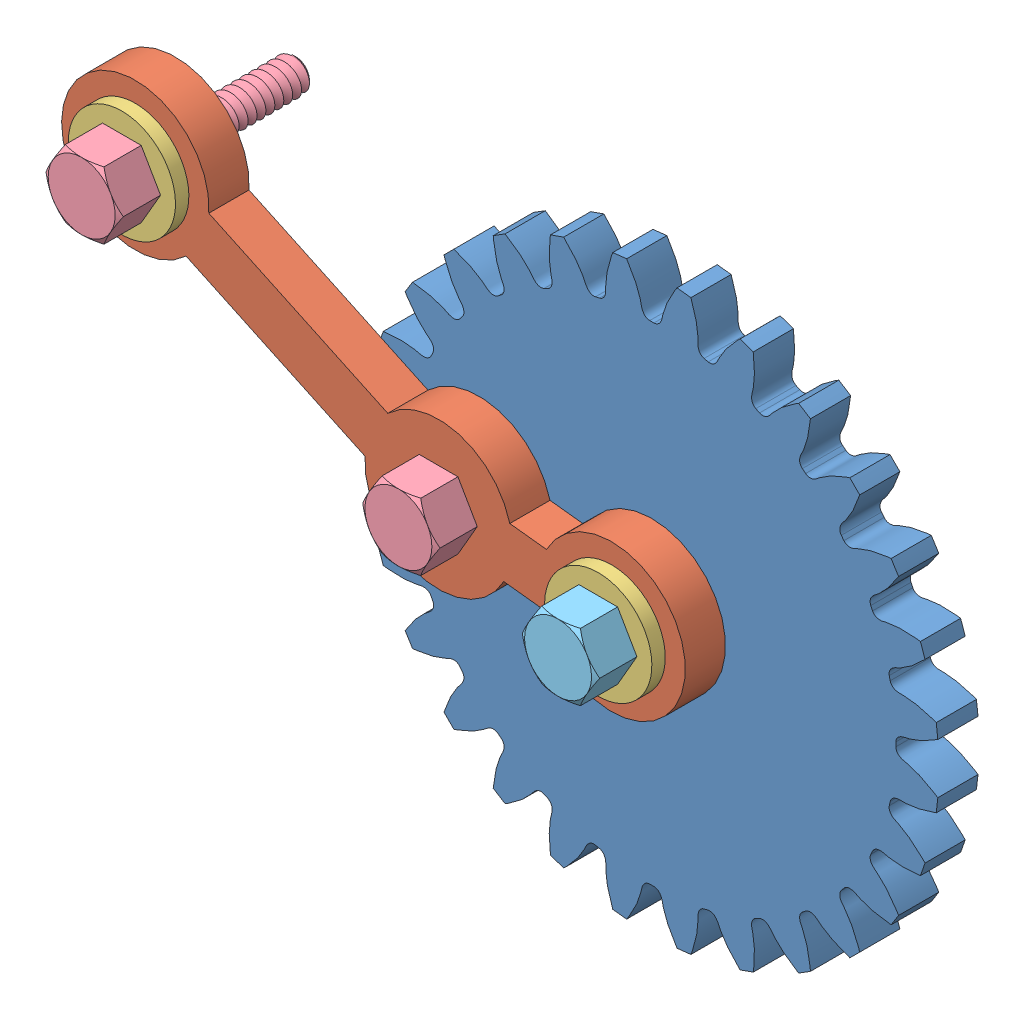
SolidWorks assembly Assem7_2, configuration Default. Lengths in mm.
Overall size (63.88 42.69 19.78).
9 component instances, 6 part files, 24 mates.
Components (placement in the parent):
- Part15-1: Part15 [Default] at origin size (42.69 42.69 3)
- Part14-1: Part14 [Default] at (0 0 4.5) x (-0.993712 0.111964 0) z (-0.111964 -0.993712 0) size (47.69 3 19)
- sajbna5-1: sajbna5 [Default] at (-35.5591 12.0572 4.5) x (1 0 0) z (0 -1 0) size (8 1 8)
- sajbna5-2: sajbna5 [Default] at (-35.5591 12.0572 0.5) x (1 0 0) z (0 -1 0) size (8 1 8)
- sajbna5-3: sajbna5 [Default] at (0 0 4.5) x (1 0 0) z (0 -1 0) size (8 1 8)
- straf3_dolg13_2-1: straf3_dolg13_2 [Default] at (-35.5591 12.0572 5.5) x (0 0 1) z (0 1 0) size (16.33 5.77 5)
- straf3_dolg13_2-2: straf3_dolg13_2 [Default] at (-12.9183 1.4555 4.5) x (0 0 1) z (0 1 0) size (16.33 5.77 5)
- straf3_dolg16_5-1: straf3_dolg16_5 [Default] at (0 0 5.5) x (0 0 1) z (0 1 0) size (19.78 5.77 5)
- navrtka6-1: navrtka6 [Default] at (-12.9183 1.4555 -3) size (5.57 5.77 3)
Mates (geometry in assembly coordinates):
- Concentric3: concentric aligned: cylinder of Part15-1 through (0 0 -1.5) axis (0 0 1) radius 1.5; cylinder of Part14-1 through (0 0 1.5) axis (0 0 1) radius 1.5
- Concentric4: concentric aligned: cylinder of Part15-1 through (-12.9183 1.4555 -1.5) axis (0 0 1) radius 1.5; cylinder of Part14-1 through (-12.9183 1.4555 1.5) axis (0 0 1) radius 1.5
- Coincident1: coincident anti-aligned: plane of Part15-1 through (0 0 1.5) normal (0 0 1); plane of Part14-1 through (0 0 1.5) normal (0 0 -1)
- Concentric6: concentric anti-aligned: cylinder of Part15-1 through (0 0 -1.5) axis (0 0 1) radius 1.5; cylinder of sajbna5-3 through (0 0 5.5) axis (0 0 -1) radius 1.5
- Coincident2: coincident anti-aligned: plane of Part14-1 through (0 0 4.5) normal (0 0 1); plane of sajbna5-3 through (0 0 4.5) normal (0 0 -1)
- Concentric8: concentric anti-aligned: cylinder of Part14-1 through (-35.5591 12.0572 1.5) axis (0 0 1) radius 1.5; cylinder of sajbna5-1 through (-35.5591 12.0572 5.5) axis (0 0 -1) radius 1.5
- Coincident3: coincident anti-aligned: plane of Part14-1 through (0 0 4.5) normal (0 0 1); plane of sajbna5-1 through (-35.5591 12.0572 4.5) normal (0 0 -1)
- Concentric9: concentric anti-aligned: cylinder of Part14-1 through (-35.5591 12.0572 1.5) axis (0 0 1) radius 1.5; cylinder of sajbna5-2 through (-35.5591 12.0572 1.5) axis (0 0 -1) radius 1.5
- Coincident4: coincident anti-aligned: plane of Part14-1 through (0 0 1.5) normal (0 0 -1); plane of sajbna5-2 through (-35.5591 12.0572 1.5) normal (0 0 1)
- Parallel1: parallel anti-aligned: plane of sajbna5-1 through (-35.5591 12.0572 4.5) normal (0 -1 0); plane of assembly through (0 0 0) normal (0 1 0)
- Parallel2: parallel anti-aligned: plane of sajbna5-2 through (-35.5591 12.0572 0.5) normal (0 -1 0); plane of assembly through (0 0 0) normal (0 1 0)
- Parallel3: parallel anti-aligned: plane of sajbna5-3 through (0 0 4.5) normal (0 -1 0); plane of assembly through (0 0 0) normal (0 1 0)
- Concentric10: concentric aligned: cylinder of Part14-1 through (-35.5591 12.0572 1.5) axis (0 0 1) radius 1.5; cylinder of straf3_dolg13_2-1 through (-35.5591 12.0572 -7.5) axis (0 0 1) radius 1.5
- Coincident8: coincident anti-aligned: plane of sajbna5-1 through (-35.5591 12.0572 5.5) normal (0 0 1); plane of straf3_dolg13_2-1 through (-35.5591 12.0572 5.5) normal (0 0 -1)
- Concentric11: concentric aligned: cylinder of Part15-1 through (-12.9183 1.4555 -1.5) axis (0 0 1) radius 1.5; cylinder of straf3_dolg13_2-2 through (-12.9183 1.4555 -8.5) axis (0 0 1) radius 1.5
- Coincident9: coincident anti-aligned: plane of Part14-1 through (0 0 4.5) normal (0 0 1); plane of straf3_dolg13_2-2 through (-12.9183 1.4555 4.5) normal (0 0 -1)
- Concentric12: concentric aligned: cylinder of Part15-1 through (0 0 -1.5) axis (0 0 1) radius 1.5; cylinder of straf3_dolg16_5-1 through (0 0 -11) axis (0 0 1) radius 1.5
- Coincident10: coincident anti-aligned: plane of sajbna5-3 through (0 0 5.5) normal (0 0 1); plane of straf3_dolg16_5-1 through (0 0 5.5) normal (0 0 -1)
- Concentric13: concentric anti-aligned: cylinder of Part15-1 through (-12.9183 1.4555 -1.5) axis (0 0 1) radius 1.5; circle of navrtka6-1
- Coincident11: coincident anti-aligned: plane of Part15-1 through (0 0 -1.5) normal (0 0 -1); plane of navrtka6-1 through (-12.9183 1.4555 -1.5) normal (0 0 1)
- Parallel4: parallel aligned: plane of straf3_dolg13_2-1 through (-35.5591 12.0572 5.5) normal (0 1 0); plane of assembly through (0 0 0) normal (0 1 0)
- Parallel5: parallel aligned: plane of straf3_dolg13_2-2 through (-12.9183 1.4555 4.5) normal (0 1 0); plane of assembly through (0 0 0) normal (0 1 0)
- Parallel6: parallel aligned: plane of straf3_dolg16_5-1 through (0 0 5.5) normal (0 1 0); plane of assembly through (0 0 0) normal (0 1 0)
- Parallel8: parallel aligned: plane of navrtka6-1 through (-12.9183 1.4555 -3) normal (0 1 0); plane of assembly through (0 0 0) normal (0 1 0)
